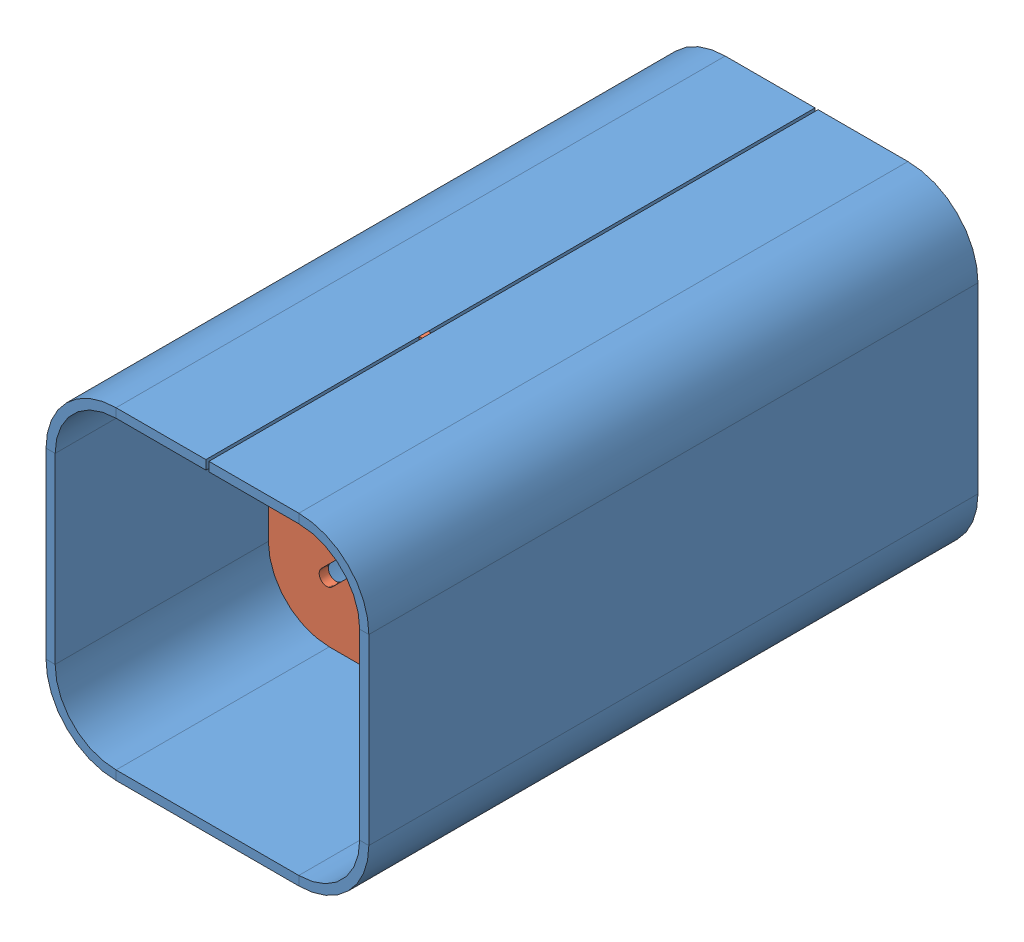
SolidWorks assembly lampe_assemblage_2, configuration Défaut. Lengths in mm.
Overall size (106 106 200).
2 component instances, 2 part files, 3 mates.
Components (placement in the parent):
- lampe_abat_jour_2-1: lampe_abat_jour_2 [Défaut] at (31.5139 -3.1457 13.5281) size (106 106 200)
- lampe_douille_2-1: lampe_douille_2 [Défaut] at (-13.1767 -3.1457 140.5281) size (106 106 3)
Mates (geometry in assembly coordinates):
- Coïncidente1: coincident: plane of lampe_abat_jour_2-1 through (-16.1777 61.8543 143.5281) normal (0 0 -1); plane of lampe_douille_2-1 through (-13.1767 -3.1457 143.5281) normal (0 0 1)
- Coïncidente2: coincident: plane of lampe_abat_jour_2-1 through (-16.1777 31.8543 143.5281) normal (0 1 0); plane of lampe_douille_2-1 through (-16.1767 31.8543 143.5281) normal (0 -1 0)
- Coïncidente3: coincident aligned: plane of lampe_abat_jour_2-1 through (-16.1767 3.0822 213.5281) normal (-1 0 0); plane of lampe_douille_2-1 through (-16.1767 31.8543 143.5281) normal (-1 0 0)
